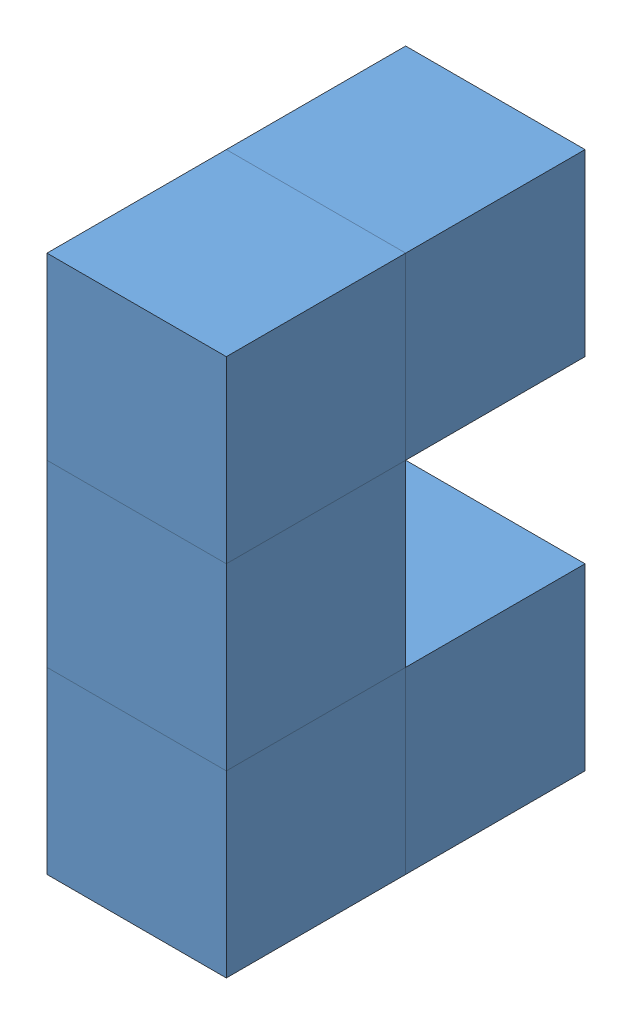
SolidWorks assembly Blue Piece, configuration Default. Lengths in mm.
Overall size (40 60 40).
6 component instances, 1 part files, 15 mates.
Components (placement in the parent):
- cube-1: cube [Default] at origin size (20 20 20)
- cube-2: cube [Default] at (0 -40 20) size (20 20 20)
- cube-3: cube [Default] at (0 0 20) size (20 20 20)
- cube-4: cube [Default] at (0 -20 20) size (20 20 20)
- cube-5: cube [Default] at (0 -40 0) size (20 20 20)
- cube-6: cube [Default] at (-20 -40 0) size (20 20 20)
Mates (geometry in assembly coordinates):
- Coincident2: coincident anti-aligned: plane of cube-1 through (10 20 10) normal (0 0 1); plane of cube-3 through (10 20 10) normal (0 0 -1)
- Coincident3: coincident aligned: plane of cube-1 through (0 20 0) normal (0 1 0); plane of cube-3 through (0 20 20) normal (0 1 0)
- Coincident4: coincident aligned: plane of cube-1 through (10 20 10) normal (1 0 0); plane of cube-3 through (10 20 30) normal (1 0 0)
- Coincident5: coincident aligned: plane of cube-3 through (10 20 30) normal (0 0 1); plane of cube-4 through (10 0 30) normal (0 0 1)
- Coincident6: coincident aligned: plane of cube-3 through (10 20 30) normal (1 0 0); plane of cube-4 through (10 0 30) normal (1 0 0)
- Coincident7: coincident anti-aligned: plane of cube-3 through (0 0 20) normal (0 -1 0); plane of cube-4 through (0 0 20) normal (0 1 0)
- Coincident8: coincident anti-aligned: plane of cube-2 through (0 -20 20) normal (0 1 0); plane of cube-4 through (0 -20 20) normal (0 -1 0)
- Coincident9: coincident aligned: plane of cube-2 through (10 -20 30) normal (1 0 0); plane of cube-4 through (10 0 30) normal (1 0 0)
- Coincident10: coincident aligned: plane of cube-2 through (10 -20 30) normal (0 0 1); plane of cube-4 through (10 0 30) normal (0 0 1)
- Coincident11: coincident anti-aligned: plane of cube-2 through (10 -20 10) normal (0 0 -1); plane of cube-5 through (10 -20 10) normal (0 0 1)
- Coincident12: coincident aligned: plane of cube-2 through (10 -20 30) normal (1 0 0); plane of cube-5 through (10 -20 10) normal (1 0 0)
- Coincident13: coincident aligned: plane of cube-2 through (0 -40 20) normal (0 -1 0); plane of cube-5 through (0 -40 0) normal (0 -1 0)
- Coincident14: coincident aligned: plane of cube-5 through (10 -20 -10) normal (0 0 -1); plane of cube-6 through (-10 -20 -10) normal (0 0 -1)
- Coincident15: coincident aligned: plane of cube-5 through (0 -40 0) normal (0 -1 0); plane of cube-6 through (-20 -40 0) normal (0 -1 0)
- Coincident16: coincident anti-aligned: plane of cube-5 through (-10 -20 10) normal (-1 0 0); plane of cube-6 through (-10 -20 10) normal (1 0 0)
